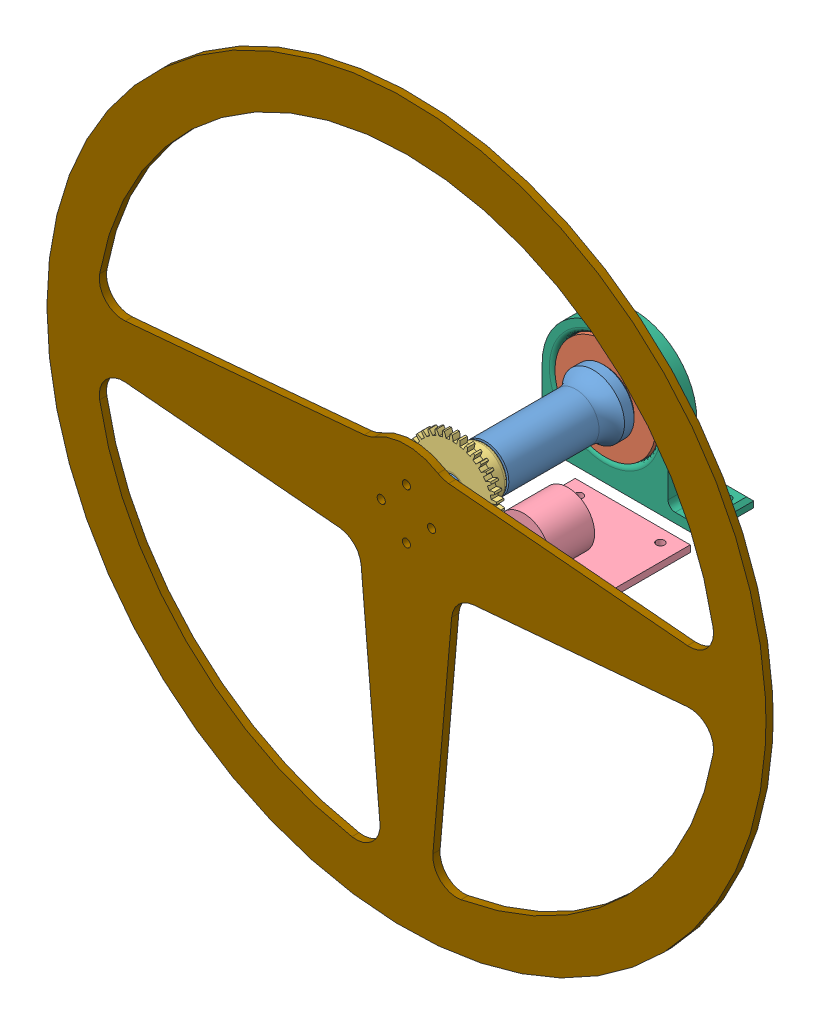
SolidWorks assembly volante, configuration Predeterminado. Lengths in mm.
Overall size (300 300 104.9).
9 component instances, 9 part files, 15 mates.
Components (placement in the parent):
- eje-1: eje [Predeterminado] at (0 0.0664 100) x (1 0 0) z (0 -1 0) size (26 92 26)
- rodamiento-1: rodamiento [Predeterminado] at (0 0.0664 50) x (-0.999914 -0.013114 0) z (0 0 -1) size (42 42 11.9)
- gear36-1: gear36 [Predeterminado] at (0 0.0664 100) x (0.998344 0.057535 0) z (0 0 1) size (37.99 37.99 14)
- pot-1: pot [Predeterminado] at (18.9037 -16.2936 84.4768) x (-1 0 0) z (0 0 -1) size (48 25 66.22)
- gear14-1: gear14 [Predeterminado] at (18.9037 -16.2936 125.9993) x (-1 0 0) z (0 0 -1) size (15.95 15.98 15)
- abrazadera-1: abrazadera [Predeterminado] at (0 0.0664 44.1) x (-1 0 0) z (0 0 -1) size (80 56.5 22)
- cople volante-1: cople volante [Predeterminado] at (0 0.0664 130) size (26 26 10)
- tapa rodamiento-1: tapa rodamiento [Predeterminado] at (0 0.0664 38) x (1 0 0) z (0 -1 0) size (26 7.75 26)
- SteeringWheel-1: SteeringWheel [Predeterminado] at (0 0.0664 130) size (300 300 3)
Mates (geometry in assembly coordinates):
- Paralelo1: parallel anti-aligned: plane of pot-1 through (42.9037 -30.1836 103.4768) normal (0 -1 0)
- Concéntrica5: concentric aligned: cylinder of rodamiento-1 through (0 0.0664 38.1) axis (0 0 1) radius 21; cylinder of abrazadera-1 through (0 0.0664 38.1) axis (0 0 1) radius 21.25
- Coincidente7: coincident aligned: plane of rodamiento-1 through (0 0.0664 38.1) normal (0 0 -1); plane of abrazadera-1 through (0 0.0664 38.1) normal (0 0 -1)
- Coincidente8: coincident aligned: plane of pot-1 through (42.9037 -30.1836 103.4768) normal (0 -1 0); plane of abrazadera-1 through (0 -30.1836 44.1) normal (0 -1 0)
- Concéntrica6: concentric anti-aligned: cylinder of eje-1 through (0 0.0664 130) axis (0 0 -1) radius 4.75; cylinder of cople volante-1 through (0 0.0664 120) axis (0 0 1) radius 5
- Coincidente9: coincident anti-aligned: plane of eje-1 through (0 0.0664 120) normal (0 0 1); plane of cople volante-1 through (0 0.0664 120) normal (0 0 -1)
- Concéntrica7: concentric aligned: cylinder of eje-1 through (0 0.0664 38) axis (0 0 1) radius 9.75; cylinder of rodamiento-1 through (0 0.0664 38.1) axis (0 0 1) radius 10
- Coincidente11: coincident anti-aligned: plane of eje-1 through (0 0.0664 50) normal (0 0 -1); plane of rodamiento-1 through (0 0.0664 50) normal (0 0 1)
- Concéntrica9: concentric aligned: cylinder of eje-1 through (0 0.0664 43) axis (0 0 -1) radius 6.25; cylinder of tapa rodamiento-1 through (0 0.0664 42.75) axis (0 0 -1) radius 6
- Coincidente12: coincident anti-aligned: plane of eje-1 through (0 0.0664 38) normal (0 0 -1); plane of tapa rodamiento-1 through (0 0.0664 38) normal (0 0 1)
- Concéntrica10: concentric aligned: cylinder of cople volante-1 through (0 10.5664 130) axis (0 0 1) radius 1.7; cylinder of SteeringWheel-1 through (0 10.5664 133) axis (0 0 1) radius 1.7
- Concéntrica11: concentric aligned: cylinder of cople volante-1 through (-10.5 0.0664 130) axis (0 0 1) radius 1.7; cylinder of SteeringWheel-1 through (-10.5 0.0664 133) axis (0 0 1) radius 1.7
- Coincidente13: coincident anti-aligned: plane of cople volante-1 through (0 0.0664 130) normal (0 0 1); plane of SteeringWheel-1 through (0 0.0664 130) normal (0 0 -1)
- Concéntrica12: concentric anti-aligned: cylinder of eje-1 through (0 0.0664 130) axis (0 0 -1) radius 4.75; cylinder of gear36-1 through (0 0.0664 100) axis (0 0 1) radius 2.5
- Coincidente14: coincident anti-aligned: plane of eje-1 through (0 0.0664 100) normal (0 0 1); plane of gear36-1 through (0 0.0664 100) normal (0 0 -1)
